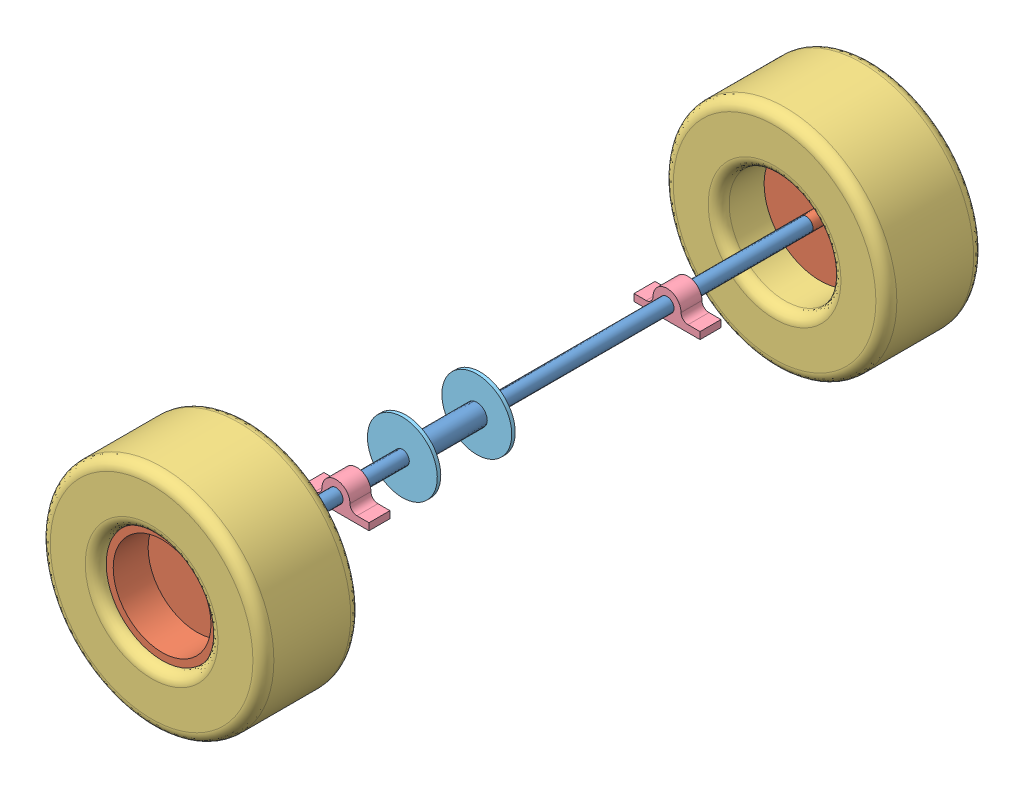
SolidWorks assembly Rear Axle Assembly, configuration Default. Lengths in mm.
Overall size (421.14 421.14 1310.5).
9 component instances, 5 part files, 18 mates.
Components (placement in the parent):
- Axle-1: Axle [Default] at (285.0621 403.6682 476.3372) x (1 0 0) z (0 -1 0) size (38.1 1120 38.1)
- Rear Wheel Hub-1: Rear Wheel Hub [Default] at (285.0621 403.6682 1596.3372) x (1 0 0) z (0 -1 0) size (203.2 101.6 203.2)
- Rear Wheel Hub-2: Rear Wheel Hub [Default] at (285.0621 403.6682 476.3372) x (0.31359 -0.949559 0) z (0.949559 0.31359 0) size (203.2 101.6 203.2)
- Rear Wheel-1: Rear Wheel [Default] at (285.0621 403.6682 1513.7872) x (0 1 0) z (1 0 0) size (406.4 177.8 406.4)
- Rear Wheel-2: Rear Wheel [Default] at (285.0621 403.6682 381.0872) x (0.999317 0.036957 0) z (0.036957 -0.999317 0) size (406.4 177.8 406.4)
- Pillow Block-1: Pillow Block [Default] at (285.0621 403.6682 716.3372) x (1 0 0) z (0 -1 0) size (120 38.1 50.8)
- Pillow Block-2: Pillow Block [Default] at (285.0621 403.6682 1318.2372) x (1 0 0) z (0 -1 0) size (120 38.1 50.8)
- Disc Break-1: Disc Break [Default] at (285.0621 403.6682 1093.9872) x (1 0 0) z (0 -1 0) size (127 6.35 127)
- Disc Break-2: Disc Break [Default] at (285.0621 403.6682 1229.3372) x (1 0 0) z (0 -1 0) size (127 6.35 127)
Mates (geometry in assembly coordinates):
- Concentric1: concentric aligned: cylinder of Axle-1 through (285.0621 403.6682 501.7372) axis (0 0 -1) radius 9.525; cylinder of Rear Wheel Hub-2 through (285.0621 403.6682 501.7372) axis (0 0 -1) radius 9.525
- Coincident1: coincident anti-aligned: plane of Axle-1 through (285.0621 403.6682 476.3372) normal (0 0 -1); plane of Rear Wheel Hub-2 through (285.0621 403.6682 476.3372) normal (0 0 1)
- Coincident2: coincident anti-aligned: plane of Axle-1 through (285.0621 403.6682 1596.3372) normal (0 0 1); plane of Rear Wheel Hub-1 through (285.0621 403.6682 1596.3372) normal (0 0 -1)
- Concentric2: concentric aligned: cylinder of Axle-1 through (285.0621 403.6682 1570.9372) axis (0 0 1) radius 9.525; cylinder of Rear Wheel Hub-1 through (285.0621 403.6682 1570.9372) axis (0 0 1) radius 9.525
- Concentric3: concentric aligned: cylinder of Rear Wheel Hub-1 through (285.0621 403.6682 1672.5372) axis (0 0 -1) radius 101.6; cylinder of Rear Wheel-1 through (285.0621 403.6682 1691.5872) axis (0 0 -1) radius 101.6
- Concentric4: concentric anti-aligned: cylinder of Rear Wheel Hub-2 through (285.0621 403.6682 400.1372) axis (0 0 1) radius 101.6; cylinder of Rear Wheel-2 through (285.0621 403.6682 558.8872) axis (0 0 -1) radius 101.6
- Concentric6: concentric aligned: cylinder of Rear Wheel Hub-2 through (285.0621 403.6682 463.6372) axis (0 0 -1) radius 88.9; cylinder of Rear Wheel-2 through (285.0621 403.6682 558.8872) axis (0 0 -1) radius 101.6
- Coincident7: coincident aligned: circle of Rear Wheel Hub-2; circle of Rear Wheel-2
- Coincident8: coincident aligned: circle of Rear Wheel Hub-1; circle of Rear Wheel-1
- Concentric7: concentric aligned: cylinder of Axle-1 through (285.0621 403.6682 1596.3372) axis (0 0 -1) radius 12.7; cylinder of Pillow Block-1 through (285.0621 403.6682 754.4372) axis (0 0 -1) radius 12.7
- Distance1: distance = 240 mm anti-aligned: plane of Pillow Block-1 through (285.0621 403.6682 716.3372) normal (0 0 -1); plane of Rear Wheel Hub-2 through (285.0621 403.6682 476.3372) normal (0 0 1)
- Concentric8: concentric aligned: cylinder of Axle-1 through (285.0621 403.6682 1596.3372) axis (0 0 -1) radius 12.7; cylinder of Pillow Block-2 through (275.8877 403.6682 792.5372) axis (0 0 -1) radius 12.7
- Distance2: distance = 240 mm anti-aligned: plane of Pillow Block-2 through (285.0621 403.6682 1356.3372) normal (0 0 1); plane of Rear Wheel Hub-1 through (285.0621 403.6682 1596.3372) normal (0 0 -1)
- Concentric9: concentric aligned: cylinder of Axle-1 through (285.0621 403.6682 1596.3372) axis (0 0 -1) radius 12.7; cylinder of Disc Break-1 through (285.0621 403.6682 1100.3372) axis (0 0 -1) radius 12.7
- Coincident10: coincident anti-aligned: plane of Axle-1 through (285.0621 403.6682 1100.3372) normal (0 0 -1); plane of Disc Break-1 through (285.0621 403.6682 1100.3372) normal (0 0 1)
- Concentric10: concentric aligned: cylinder of Axle-1 through (285.0621 403.6682 1596.3372) axis (0 0 -1) radius 12.7; cylinder of Disc Break-2 through (285.0621 403.6682 1235.6872) axis (0 0 -1) radius 12.7
- Coincident11: coincident anti-aligned: plane of Axle-1 through (285.0621 403.6682 1229.3372) normal (0 0 1); plane of Disc Break-2 through (285.0621 403.6682 1229.3372) normal (0 0 -1)
- Coincident12: coincident aligned: plane of Pillow Block-1 through (285.0621 378.2682 754.4372) normal (0 -1 0); plane of Pillow Block-2 through (285.0621 378.2682 1356.3372) normal (0 -1 0)
